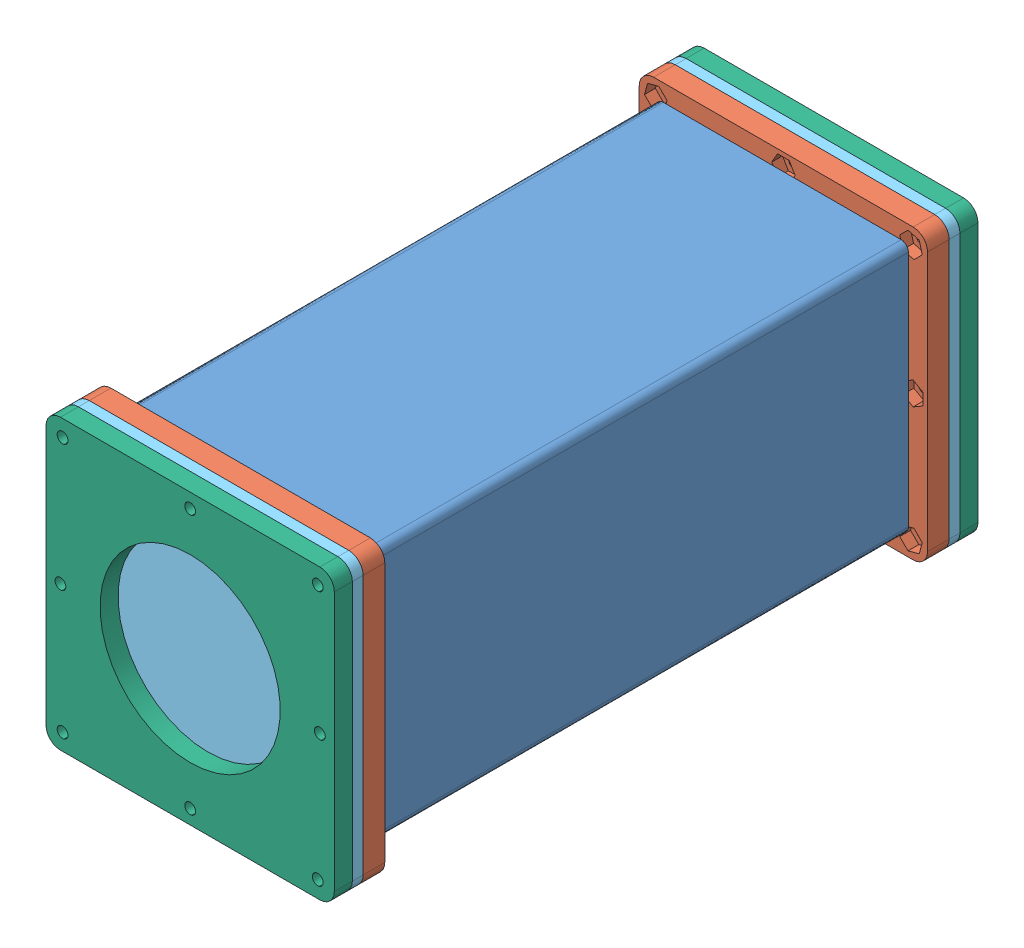
SolidWorks assembly 方形密封舱, configuration 默认. Lengths in mm.
Overall size (92.6 92 178).
13 component instances, 6 part files, 20 mates.
Components (placement in the parent):
- 密封舱-亚克力段70-1: 密封舱-亚克力段70 [默认] at (7.5922 -1.2732 140) size (70 70 150)
- 矩形法兰70708080-1: 矩形法兰70708080 [默认] at (7.2922 -1.5732 290) x (1 0 0) z (0 -1 0) size (80 26.9 80)
- 矩形法兰70708080-2: 矩形法兰70708080 [默认] at (7.8922 -1.5732 140) x (1 0 0) z (0 1 0) size (80 26.9 80)
- 3.55矩形氟橡胶-1: 3.55矩形氟橡胶 [默认] at (7.8833 -1.3232 145.6959) x (0 1 0) z (0.00069 0 -1) size (64.79 64.74 4.92)
- 3.55矩形氟橡胶-2: 3.55矩形氟橡胶 [默认] at (7.3995 -1.2605 277.2066) size (64.79 64.74 4.92)
- 3.55矩形氟橡胶-3: 3.55矩形氟橡胶 [默认] at (6.8133 -1.5822 284.2743) size (64.79 64.74 4.92)
- 3.55矩形氟橡胶-4: 3.55矩形氟橡胶 [默认] at (7.7739 -1.2858 153.0152) size (64.79 64.74 4.92)
- 60氟橡胶圈-1: 60氟橡胶圈 [默认] at (7.8922 -1.5732 135.6037) x (0.95369 0.300791 0) z (-0.300791 0.95369 0) size (67.1 3.55 67.1)
- 60氟橡胶圈-2: 60氟橡胶圈 [默认] at (7.2922 -1.5732 297.7537) x (0.472409 0.881379 0) z (-0.881379 0.472409 0) size (67.1 3.55 67.1)
- 矩形法兰盖80803-1: 矩形法兰盖80803 [默认] at (7.8922 -1.5732 134) x (1 0 0) z (0 1 0) size (80 3 80)
- 矩形法兰盖80803-2: 矩形法兰盖80803 [默认] at (7.2922 -1.5732 299) x (1 0 0) z (0 1 0) size (80 3 80)
- 矩形法兰保护框-1: 矩形法兰保护框 [默认] at (7.8922 -1.5732 131) x (1 0 0) z (0 1 0) size (92 5 92)
- 矩形法兰保护框-2: 矩形法兰保护框 [默认] at (7.2922 -1.5732 304) x (1 0 0) z (0 1 0) size (92 5 92)
Mates (geometry in assembly coordinates):
- 重合1: coincident: plane of assembly; plane of assembly; plane of 密封舱-亚克力段70-1 through (7.5922 -1.2732 290) normal (0 0 1); plane of 矩形法兰70708080-1 through (7.2922 -1.5732 290) normal (0 0 -1)
- 重合2: coincident: plane of assembly; plane of assembly; plane of 密封舱-亚克力段70-1 through (7.5922 -1.2732 140) normal (0 0 -1); plane of 矩形法兰70708080-2 through (7.8922 -1.5732 140) normal (0 0 1)
- 重合3: coincident: plane of assembly; plane of assembly; plane of 密封舱-亚克力段70-1 through (-24.4078 -33.2732 290) normal (0 1 0); plane of 矩形法兰70708080-2 through (39.5922 -33.2732 160.9) normal (0 -1 0)
- 重合4: coincident: plane of assembly; plane of assembly; plane of 密封舱-亚克力段70-1 through (39.5922 30.7268 290) normal (-1 0 0); plane of 矩形法兰70708080-2 through (39.5922 30.1268 160.9) normal (1 0 0)
- 重合5: coincident: plane of assembly; plane of assembly; plane of 密封舱-亚克力段70-1 through (-24.4078 30.7268 290) normal (1 0 0); plane of 矩形法兰70708080-1 through (-24.4078 -33.2732 269.1) normal (-1 0 0)
- 重合6: coincident: plane of assembly; plane of assembly; plane of 密封舱-亚克力段70-1 through (-24.4078 -33.2732 290) normal (0 1 0); plane of 矩形法兰70708080-1 through (38.9922 -33.2732 269.1) normal (0 -1 0)
- 相切5: tangent: plane of assembly; plane of 矩形法兰70708080-2 through (7.8922 -1.5732 147.45) normal (0 0 -1); face of 3.55矩形氟橡胶-1
- 相切6: tangent: plane of assembly; plane of 矩形法兰70708080-2 through (36.5922 27.1268 147.45) normal (0 1 0); face of 3.55矩形氟橡胶-1
- 相切8: tangent: plane of assembly; torus of assembly; plane of 矩形法兰70708080-2 through (7.8922 -1.5732 135.7) normal (0 0 -1); torus of 60氟橡胶圈-1
- 重合10: coincident: line of assembly; axis of 矩形法兰70708080-2 through (7.8922 -1.5732 160.9) axis (0 0 -1); axis of 60氟橡胶圈-1 through (7.8922 -1.5732 152.917) axis (0 0 -1)
- 重合12: coincident: line of assembly; axis of 矩形法兰70708080-1 through (7.2922 -1.5732 269.1) axis (0 0 1); axis of 60氟橡胶圈-2 through (7.2922 -1.5732 315.067) axis (0 0 -1)
- 相切11: tangent: plane of assembly; torus of assembly; plane of 矩形法兰70708080-1 through (7.2922 -1.5732 294.3) normal (0 0 1); torus of 60氟橡胶圈-2
- 重合13: coincident: plane of assembly; plane of assembly; plane of 矩形法兰70708080-2 through (7.8922 -1.5732 134) normal (0 0 -1); plane of 矩形法兰盖80803-1 through (7.8922 -1.5732 134) normal (0 0 1)
- 同心1: concentric: circle of assembly; circle of assembly; circle of 矩形法兰70708080-2; circle of 矩形法兰盖80803-1
- 重合14: coincident: plane of assembly; plane of assembly; plane of 矩形法兰盖80803-1 through (7.8922 -1.5732 131) normal (0 0 -1); plane of 矩形法兰保护框-1 through (7.8922 -1.5732 131) normal (0 0 1)
- 同心2: concentric: circle of assembly; circle of assembly; circle of 矩形法兰盖80803-1; circle of 矩形法兰保护框-1
- 重合16: coincident: plane of assembly; plane of assembly; plane of 矩形法兰70708080-1 through (7.2922 -1.5732 296) normal (0 0 1); plane of 矩形法兰盖80803-2 through (7.2922 -1.5732 296) normal (0 0 -1)
- 同心3: concentric: circle of assembly; circle of assembly; circle of 矩形法兰70708080-1; circle of 矩形法兰盖80803-2
- 重合18: coincident: plane of assembly; plane of assembly; plane of 矩形法兰盖80803-2 through (7.2922 -1.5732 299) normal (0 0 1); plane of 矩形法兰保护框-2 through (7.2922 -1.5732 299) normal (0 0 -1)
- 同心4: concentric: circle of assembly; circle of assembly; circle of 矩形法兰盖80803-2; circle of 矩形法兰保护框-2
